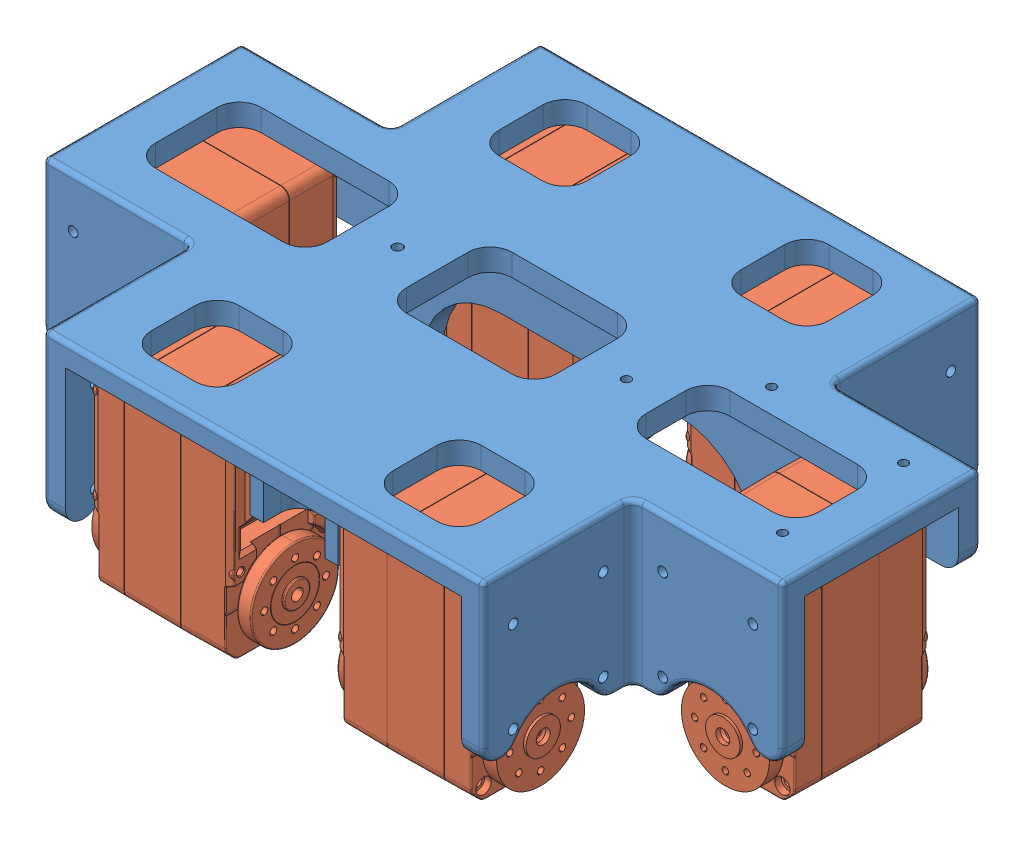
SolidWorks assembly Assem1, configuration Default. Lengths in mm.
Overall size (168 59.68 113).
8 component instances, 2 part files, 3 mates.
Components (placement in the parent):
- link0-1: link0 [Default] x (1 0 0) z (0 0 -1) size (168 59.68 113)
  - platform-v4-1: platform-v4 [Default] at (0 36.8 -17.5) x (-1 0 0) z (0 0 1) size (168 36.8 113)
  - Servo-LX-16A-1: Servo-LX-16A [Default] at (37.5 14.825 39.5) x (0 -1 0) z (0 0 1) size (54.66 37.3 26.46)
  - Servo-LX-16A-2: Servo-LX-16A [Default] at (-37.5 14.825 39.5) x (0 -1 0) z (0 0 -1) size (54.66 37.3 26.46)
  - Servo-LX-16A-3: Servo-LX-16A [Default] at (-67 14.825 -10) x (0 -1 0) z (1 0 0) size (54.66 37.3 26.46)
  - Servo-LX-16A-4: Servo-LX-16A [Default] at (-37.5 14.825 -39.5) x (0 -1 0) z (0 0 -1) size (54.66 37.3 26.46)
  - Servo-LX-16A-5: Servo-LX-16A [Default] at (37.5 14.825 -39.5) x (0 -1 0) z (0 0 1) size (54.66 37.3 26.46)
  - Servo-LX-16A-6: Servo-LX-16A [Default] at (67 14.825 -10) x (0 -1 0) z (1 0 0) size (54.66 37.3 26.46)
Mates (geometry in assembly coordinates):
- Coincident1: coincident: plane of assembly; plane of link0-1/platform-v4-1 through (0 0 17.5) normal (0 1 0); plane of assembly
- Coincident2: coincident: plane of assembly; plane of link0-1/platform-v4-1 through (0 -36.8 17.5) normal (-1 0 0); plane of assembly
- Coincident3: coincident anti-aligned: plane of link0-1/platform-v4-1 through (0 -36.8 0) normal (0 0 -1)
